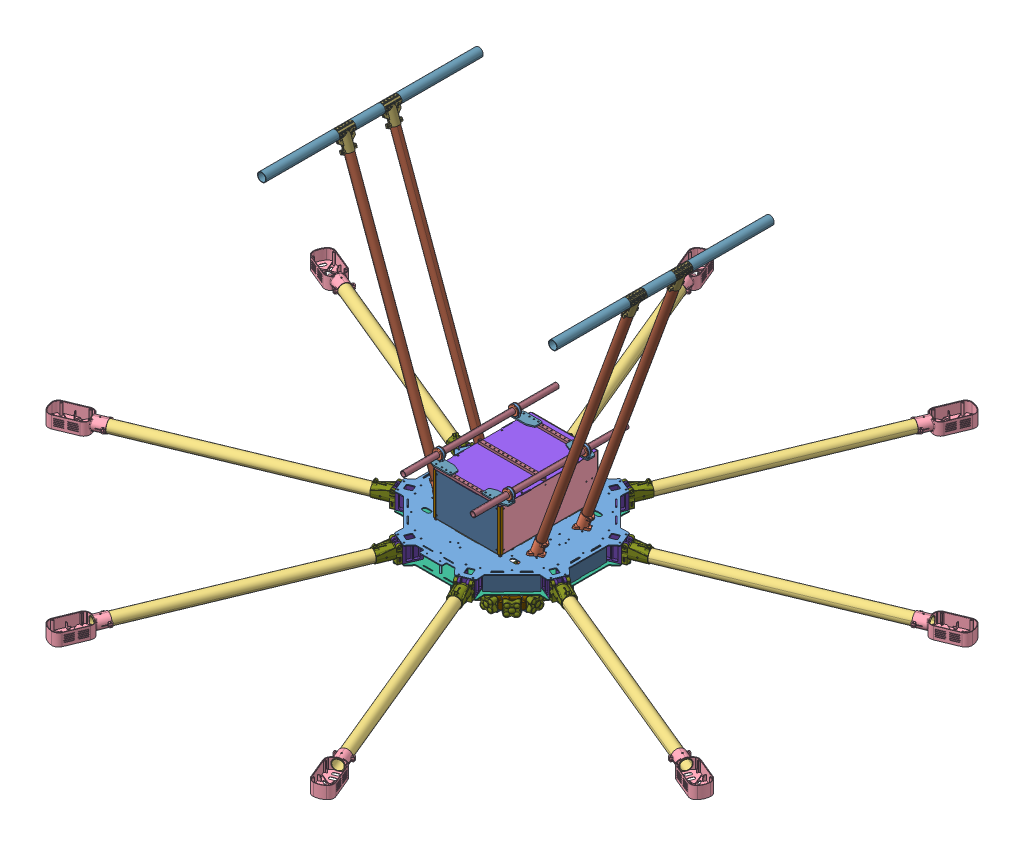
SolidWorks assembly X8_Max-frame with Teraranger mount, configuration Default. Lengths in mm.
Overall size (1514.24 796.89 1514.24).
169 component instances, 38 part files, 6 mates.
Components (placement in the parent):
- X8 Max Assem-2.STEP-1: X8 Max Assem-2.STEP [Default] at origin size (1514.24 672.95 1514.24)
  - Ensamblaje Caja de baterias.STEP-1: Ensamblaje Caja de baterias.STEP [Default] at (-4.4674 -57.1682 2.6) size (189.05 134.33 225.1)
    - Soporte Tubos Assem.STEP-1: Soporte Tubos Assem.STEP [Default] at (29.4599 122.1453 316.55) x (-1 0 0) z (0 0 1) size (30.05 30.05 9.5)
      - Soporte Tubos 1.2.STEP-1: Soporte Tubos 1.2.STEP [Default] at (-57.7355 6.8516 -2.2) size (22 22 4.4)
      - Soporte Tubos 1.1.STEP-1: Soporte Tubos 1.1.STEP [Default] at (-57.7355 6.8516 -4.7) x (0.866047 0.499962 0) z (0 0 1) size (22 22 9.5)
    - Soporte Tubos Assem.STEP-2: Soporte Tubos Assem.STEP [Default] at (-129.5401 122.1453 316.55) x (-1 0 0) z (0 0 1) size (30.05 30.05 9.5)
      - Soporte Tubos 1.2.STEP-1: Soporte Tubos 1.2.STEP [Default] at (-57.7355 6.8516 -2.2) size (22 22 4.4)
      - Soporte Tubos 1.1.STEP-1: Soporte Tubos 1.1.STEP [Default] at (-57.7355 6.8516 -4.7) x (0.866047 0.499962 0) z (0 0 1) size (22 22 9.5)
    - Soporte Tubos Assem.STEP-3: Soporte Tubos Assem.STEP [Default] at (29.4599 122.1453 143.55) x (-1 0 0) z (0 0 1) size (30.05 30.05 9.5)
      - Soporte Tubos 1.2.STEP-1: Soporte Tubos 1.2.STEP [Default] at (-57.7355 6.8516 -2.2) size (22 22 4.4)
      - Soporte Tubos 1.1.STEP-1: Soporte Tubos 1.1.STEP [Default] at (-57.7355 6.8516 -4.7) x (0.866047 0.499962 0) z (0 0 1) size (22 22 9.5)
    - Soporte Tubos Assem.STEP-4: Soporte Tubos Assem.STEP [Default] at (-129.5401 122.1453 143.55) x (-1 0 0) z (0 0 1) size (30.05 30.05 9.5)
      - Soporte Tubos 1.2.STEP-1: Soporte Tubos 1.2.STEP [Default] at (-57.7355 6.8516 -2.2) size (22 22 4.4)
      - Soporte Tubos 1.1.STEP-1: Soporte Tubos 1.1.STEP [Default] at (-57.7355 6.8516 -4.7) x (0.866047 0.499962 0) z (0 0 1) size (22 22 9.5)
    - Frame Standard FC Bateria Placa Superior.STEP-1: Frame Standard FC Bateria Placa Superior.STEP [Default] at (7.6954 -1.0063 222.5) size (155 1 223)
    - Frame Standard FC Bateria Pared Lateral Cerradura.STEP-1: Frame Standard FC Bateria Pared Lateral Cerradura.STEP [Default] at (84.1954 47.4937 219.45) x (0 0 -1) z (0 1 0) size (216 1 97)
    - Frame Standard FC Bateria Pared Lateral Visagras.STEP-1: Frame Standard FC Bateria Pared Lateral Visagras.STEP [Default] at (-67.8046 47.4937 219.45) x (0 0 -1) z (0 1 0) size (216 1 97)
    - Columna Soporte lateral.STEP-1: Columna Soporte lateral.STEP [Default] at (-65.3046 94.9937 130.05) x (1 0 0) z (0 -1 0) size (5 7 95)
    - Columna Soporte lateral.STEP-2: Columna Soporte lateral.STEP [Default] at (-65.3046 94.9937 230.05) x (1 0 0) z (0 -1 0) size (5 7 95)
    - Columna Soporte lateral.STEP-3: Columna Soporte lateral.STEP [Default] at (80.6954 94.9937 130.05) x (-1 0 0) z (0 -1 0) size (5 7 95)
    - Columna Soporte lateral.STEP-4: Columna Soporte lateral.STEP [Default] at (80.6954 94.9937 230.05) x (-1 0 0) z (0 -1 0) size (5 7 95)
    - Separador 95mm.STEP-1: Separador 95mm.STEP [Default] at (80.6954 94.9937 180.05) x (0.181479 0 -0.983395) z (0 -1 0) size (4.5 4.5 95)
    - Separador 95mm.STEP-2: Separador 95mm.STEP [Default] at (80.6954 94.9937 280.05) x (-0.225094 0 -0.974337) z (0 -1 0) size (4.5 4.5 95)
    - Separador 95mm.STEP-3: Separador 95mm.STEP [Default] at (-65.3046 -0.0063 180.05) x (-0.848491 0 0.529211) z (0 1 0) size (4.5 4.5 95)
    - Separador 95mm.STEP-4: Separador 95mm.STEP [Default] at (-65.3046 94.9937 280.05) x (0.989316 0 -0.145784) z (0 -1 0) size (4.5 4.5 95)
    - Frame Standard FC Bateria Placa Inferior.STEP-1: Frame Standard FC Bateria Placa Inferior.STEP [Default] at (7.6954 94.9937 222.5) size (155 1 223)
    - Columna Soporte Esquinas.STEP-1: Columna Soporte Esquinas.STEP [Default] at (-68.8046 94.9937 333.5) x (1 0 0) z (0 -1 0) size (10.5 10.5 95)
    - Columna Soporte Esquinas.STEP-2: Columna Soporte Esquinas.STEP [Default] at (84.1954 -0.0063 333.5) x (-1 0 0) z (0 1 0) size (10.5 10.5 95)
    - Frame Standard FC Bateria Placa Delantera.STEP-1: Frame Standard FC Bateria Placa Delantera.STEP [Default] at (7.6954 47.4437 333.5) x (1 0 0) z (0 1 0) size (140.5 1 97)
    - Frame Standard FC Bateria Separador.STEP-1: Frame Standard FC Bateria Separador.STEP [Default] at (-65.3046 -1.0063 230.05) x (0 0 1) z (1 0 0) size (206.1 3 8.1)
    - Frame Standard FC Bateria Separador.STEP-2: Frame Standard FC Bateria Separador.STEP [Default] at (80.6954 -4.0063 230.05) x (0 0 1) z (-1 0 0) size (206.1 3 8.1)
    - Frame Standard FC Bateria Placa Trasera.STEP-1: Frame Standard FC Bateria Placa Trasera.STEP [Default] at (9.1954 48.2937 111.45) x (1 0 0) z (0 1 0) size (151 1.5 95.4)
    - Rieles.STEP-1: Rieles.STEP [Default] at (7.6954 95.9937 330.05) x (1 0 0) z (0 1 0) size (153 7.6 5.5)
    - Rieles.STEP-2: Rieles.STEP [Default] at (7.6954 95.9937 130.05) x (1 0 0) z (0 1 0) size (153 7.6 5.5)
    - Rieles.STEP-3: Rieles.STEP [Default] at (7.6954 95.9937 230.05) x (1 0 0) z (0 1 0) size (153 7.6 5.5)
    - Frame Standard FC Bateria Placa Soporte Tubos.STEP-1: Frame Standard FC Bateria Placa Soporte Tubos.STEP [Default] at (7.1954 104.2937 340.05) x (-1 0 0) z (0 0 1) size (55.5 2.8 23.5)
    - Frame Standard FC Bateria Placa Soporte Tubos.STEP-2: Frame Standard FC Bateria Placa Soporte Tubos.STEP [Default] at (8.1954 101.4937 340.05) size (55.5 2.8 23.5)
    - Frame Standard FC Bateria Placa Soporte Tubos.STEP-3: Frame Standard FC Bateria Placa Soporte Tubos.STEP [Default] at (8.1954 104.2937 120.05) x (1 0 0) z (0 0 -1) size (55.5 2.8 23.5)
    - Frame Standard FC Bateria Placa Soporte Tubos.STEP-4: Frame Standard FC Bateria Placa Soporte Tubos.STEP [Default] at (7.1954 101.4937 120.05) x (-1 0 0) z (0 0 -1) size (55.5 2.8 23.5)
  - F25A201903000_ASM.STEP-1: F25A201903000_ASM.STEP [Default] at (50.0183 -63.1744 77.2248) x (0.92388 0 0.382683) z (0 1 0) size (32.71 81.51 45.27)
    - ADMI4DDBV6KN_ASM.STEP-1: ADMI4DDBV6KN_ASM.STEP [Default] at origin size (32.71 81.51 45.27)
      - ADMI4DDBV6KN_1.STEP-1: ADMI4DDBV6KN_1.STEP [Default] at origin size (9 9 21)
      - ADMI4DDBV6KN_2.STEP-1: ADMI4DDBV6KN_2.STEP [Default] at origin size (32.51 45.52 39.01)
      - ADMI4DDBV6KN_3.STEP-1: ADMI4DDBV6KN_3.STEP [Default] at origin size (32.51 45.51 38.51)
      - ADMI4DDBV6KN_4.STEP-1: ADMI4DDBV6KN_4.STEP [Default] at origin size (32.5 3 3)
  - F25A201903000_ASM.STEP-2: F25A201903000_ASM.STEP [Default] at (146.2159 -63.1744 155.8336) x (0.382683 0 0.92388) z (0 1 0) size (32.71 81.51 45.27)
    - ADMI4DDBV6KN_ASM.STEP-1: ADMI4DDBV6KN_ASM.STEP [Default] at origin size (32.71 81.51 45.27)
      - ADMI4DDBV6KN_1.STEP-1: ADMI4DDBV6KN_1.STEP [Default] at origin size (9 9 21)
      - ADMI4DDBV6KN_2.STEP-1: ADMI4DDBV6KN_2.STEP [Default] at origin size (32.51 45.52 39.01)
      - ADMI4DDBV6KN_3.STEP-1: ADMI4DDBV6KN_3.STEP [Default] at origin size (32.51 45.51 38.51)
      - ADMI4DDBV6KN_4.STEP-1: ADMI4DDBV6KN_4.STEP [Default] at origin size (32.5 3 3)
  - F25A201903000_ASM.STEP-3: F25A201903000_ASM.STEP [Default] at (158.6531 -63.1744 279.4403) x (-0.382683 0 0.92388) z (0 1 0) size (32.71 81.51 45.27)
    - ADMI4DDBV6KN_ASM.STEP-1: ADMI4DDBV6KN_ASM.STEP [Default] at origin size (32.71 81.51 45.27)
      - ADMI4DDBV6KN_1.STEP-1: ADMI4DDBV6KN_1.STEP [Default] at origin size (9 9 21)
      - ADMI4DDBV6KN_2.STEP-1: ADMI4DDBV6KN_2.STEP [Default] at origin size (32.51 45.52 39.01)
      - ADMI4DDBV6KN_3.STEP-1: ADMI4DDBV6KN_3.STEP [Default] at origin size (32.51 45.51 38.51)
      - ADMI4DDBV6KN_4.STEP-1: ADMI4DDBV6KN_4.STEP [Default] at origin size (32.5 3 3)
  - F25A201903000_ASM.STEP-4: F25A201903000_ASM.STEP [Default] at (80.0444 -63.1744 375.6379) x (-0.92388 0 0.382683) z (0 1 0) size (32.71 81.51 45.27)
    - ADMI4DDBV6KN_ASM.STEP-1: ADMI4DDBV6KN_ASM.STEP [Default] at origin size (32.71 81.51 45.27)
      - ADMI4DDBV6KN_1.STEP-1: ADMI4DDBV6KN_1.STEP [Default] at origin size (9 9 21)
      - ADMI4DDBV6KN_2.STEP-1: ADMI4DDBV6KN_2.STEP [Default] at origin size (32.51 45.52 39.01)
      - ADMI4DDBV6KN_3.STEP-1: ADMI4DDBV6KN_3.STEP [Default] at origin size (32.51 45.51 38.51)
      - ADMI4DDBV6KN_4.STEP-1: ADMI4DDBV6KN_4.STEP [Default] at origin size (32.5 3 3)
  - F25A201903000_ASM.STEP-5: F25A201903000_ASM.STEP [Default] at (-43.5623 -63.1744 388.0752) x (-0.92388 0 -0.382683) z (0 1 0) size (32.71 81.51 45.27)
    - ADMI4DDBV6KN_ASM.STEP-1: ADMI4DDBV6KN_ASM.STEP [Default] at origin size (32.71 81.51 45.27)
      - ADMI4DDBV6KN_1.STEP-1: ADMI4DDBV6KN_1.STEP [Default] at origin size (9 9 21)
      - ADMI4DDBV6KN_2.STEP-1: ADMI4DDBV6KN_2.STEP [Default] at origin size (32.51 45.52 39.01)
      - ADMI4DDBV6KN_3.STEP-1: ADMI4DDBV6KN_3.STEP [Default] at origin size (32.51 45.51 38.51)
      - ADMI4DDBV6KN_4.STEP-1: ADMI4DDBV6KN_4.STEP [Default] at origin size (32.5 3 3)
  - F25A201903000_ASM.STEP-6: F25A201903000_ASM.STEP [Default] at (-139.7599 -63.1744 309.4664) x (-0.382683 0 -0.92388) z (0 1 0) size (32.71 81.51 45.27)
    - ADMI4DDBV6KN_ASM.STEP-1: ADMI4DDBV6KN_ASM.STEP [Default] at origin size (32.71 81.51 45.27)
      - ADMI4DDBV6KN_1.STEP-1: ADMI4DDBV6KN_1.STEP [Default] at origin size (9 9 21)
      - ADMI4DDBV6KN_2.STEP-1: ADMI4DDBV6KN_2.STEP [Default] at origin size (32.51 45.52 39.01)
      - ADMI4DDBV6KN_3.STEP-1: ADMI4DDBV6KN_3.STEP [Default] at origin size (32.51 45.51 38.51)
      - ADMI4DDBV6KN_4.STEP-1: ADMI4DDBV6KN_4.STEP [Default] at origin size (32.5 3 3)
  - F25A201903000_ASM.STEP-7: F25A201903000_ASM.STEP [Default] at (-152.1972 -63.1744 185.8597) x (0.382683 0 -0.92388) z (0 1 0) size (32.71 81.51 45.27)
    - ADMI4DDBV6KN_ASM.STEP-1: ADMI4DDBV6KN_ASM.STEP [Default] at origin size (32.71 81.51 45.27)
      - ADMI4DDBV6KN_1.STEP-1: ADMI4DDBV6KN_1.STEP [Default] at origin size (9 9 21)
      - ADMI4DDBV6KN_2.STEP-1: ADMI4DDBV6KN_2.STEP [Default] at origin size (32.51 45.52 39.01)
      - ADMI4DDBV6KN_3.STEP-1: ADMI4DDBV6KN_3.STEP [Default] at origin size (32.51 45.51 38.51)
      - ADMI4DDBV6KN_4.STEP-1: ADMI4DDBV6KN_4.STEP [Default] at origin size (32.5 3 3)
  - F25A201903000_ASM.STEP-8: F25A201903000_ASM.STEP [Default] at (-73.5884 -63.1744 89.6621) x (0.92388 0 -0.382683) z (0 1 0) size (32.71 81.51 45.27)
    - ADMI4DDBV6KN_ASM.STEP-1: ADMI4DDBV6KN_ASM.STEP [Default] at origin size (32.71 81.51 45.27)
      - ADMI4DDBV6KN_1.STEP-1: ADMI4DDBV6KN_1.STEP [Default] at origin size (9 9 21)
      - ADMI4DDBV6KN_2.STEP-1: ADMI4DDBV6KN_2.STEP [Default] at origin size (32.51 45.52 39.01)
      - ADMI4DDBV6KN_3.STEP-1: ADMI4DDBV6KN_3.STEP [Default] at origin size (32.51 45.51 38.51)
      - ADMI4DDBV6KN_4.STEP-1: ADMI4DDBV6KN_4.STEP [Default] at origin size (32.5 3 3)
  - Frame X8 Max FC Cuerpo Plato Inferior.STEP-1: Frame X8 Max FC Cuerpo Plato Inferior.STEP [Default] at (3.228 -61.1744 232.65) x (1 0 0) z (0 -1 0) size (378.3 378.3 2)
  - Soporte Pata.STEP-1: Soporte Pata.STEP [Default] at (-102.0735 -69.0149 180.4) x (0.939693 0.34202 0) z (-0.34202 0.939693 0) size (28.4 36.17 38.5)
  - Soporte Pata.STEP-2: Soporte Pata.STEP [Default] at (-102.0735 -69.0149 284.9) x (0.939693 0.34202 0) z (-0.34202 0.939693 0) size (28.4 36.17 38.5)
  - Soporte Pata.STEP-3: Soporte Pata.STEP [Default] at (108.5295 -69.0149 284.9) x (-0.939693 0.34202 0) z (0.34202 0.939693 0) size (28.4 36.17 38.5)
  - Soporte Pata.STEP-4: Soporte Pata.STEP [Default] at (108.5295 -69.0149 180.4) x (-0.939693 0.34202 0) z (0.34202 0.939693 0) size (28.4 36.17 38.5)
  - Frame X8 Max FC Tubo Brazo.STEP-1: Frame X8 Max FC Tubo Brazo.STEP [Default] at (83.4002 -81.6744 39.0972) x (0.202315 -0.975728 0.083802) z (0.901455 0.218985 0.373395) size (25 524 25)
  - MINI-DJZ-25-SLIM.STEP-1: MINI-DJZ-25-SLIM.STEP [Default] at (300.4461 -98.1744 -484.8979) x (-0.382683 0 0.92388) z (0 1 0) size (106.78 43.6 30.2)
  - MINI-DJZ-25-SLIM.STEP-2: MINI-DJZ-25-SLIM.STEP [Default] at (720.7759 -98.1744 -64.5681) x (-0.92388 0 0.382683) z (0 1 0) size (106.78 43.6 30.2)
  - MINI-DJZ-25-SLIM.STEP-3: MINI-DJZ-25-SLIM.STEP [Default] at (720.7759 -98.1744 529.8681) x (-0.92388 0 -0.382683) z (0 1 0) size (106.78 43.6 30.2)
  - MINI-DJZ-25-SLIM.STEP-4: MINI-DJZ-25-SLIM.STEP [Default] at (300.4461 -98.1744 950.1979) x (-0.382683 0 -0.92388) z (0 1 0) size (106.78 43.6 30.2)
  - MINI-DJZ-25-SLIM.STEP-5: MINI-DJZ-25-SLIM.STEP [Default] at (-293.9901 -98.1744 950.1979) x (0.382683 0 -0.92388) z (0 1 0) size (106.78 43.6 30.2)
  - MINI-DJZ-25-SLIM.STEP-6: MINI-DJZ-25-SLIM.STEP [Default] at (-714.3199 -98.1744 529.8681) x (0.92388 0 -0.382683) z (0 1 0) size (106.78 43.6 30.2)
  - MINI-DJZ-25-SLIM.STEP-7: MINI-DJZ-25-SLIM.STEP [Default] at (-714.3199 -98.1744 -64.5681) x (0.92388 0 0.382683) z (0 1 0) size (106.78 43.6 30.2)
  - MINI-DJZ-25-SLIM.STEP-8: MINI-DJZ-25-SLIM.STEP [Default] at (-293.9901 -98.1744 -484.8979) x (0.382683 0 0.92388) z (0 1 0) size (106.78 43.6 30.2)
  - Frame X8 Max FC Tubo Brazo.STEP-2: Frame X8 Max FC Tubo Brazo.STEP [Default] at (196.7808 -81.6744 152.4778) x (0.083802 -0.975728 0.202315) z (0.373395 0.218985 0.901455) size (25 524 25)
  - Frame X8 Max FC Tubo Brazo.STEP-3: Frame X8 Max FC Tubo Brazo.STEP [Default] at (196.7808 -81.6744 312.8222) x (-0.083802 -0.975728 0.202315) z (-0.373395 0.218985 0.901455) size (25 524 25)
  - Frame X8 Max FC Tubo Brazo.STEP-4: Frame X8 Max FC Tubo Brazo.STEP [Default] at (83.4002 -81.6744 426.2028) x (-0.202315 -0.975728 0.083802) z (-0.901455 0.218985 0.373395) size (25 524 25)
  - Frame X8 Max FC Tubo Brazo.STEP-5: Frame X8 Max FC Tubo Brazo.STEP [Default] at (-76.9442 -81.6744 426.2028) x (-0.202315 -0.975728 -0.083802) z (-0.901455 0.218985 -0.373395) size (25 524 25)
  - Frame X8 Max FC Tubo Brazo.STEP-6: Frame X8 Max FC Tubo Brazo.STEP [Default] at (-190.3248 -81.6744 312.8222) x (-0.083802 -0.975728 -0.202315) z (-0.373395 0.218985 -0.901455) size (25 524 25)
  - Frame X8 Max FC Tubo Brazo.STEP-7: Frame X8 Max FC Tubo Brazo.STEP [Default] at (-190.3248 -81.6744 152.4778) x (0.083802 -0.975728 -0.202315) z (0.373395 0.218985 -0.901455) size (25 524 25)
  - Frame X8 Max FC Tubo Brazo.STEP-8: Frame X8 Max FC Tubo Brazo.STEP [Default] at (-76.9442 -81.6744 39.0972) x (0.202315 -0.975728 -0.083802) z (0.901455 0.218985 -0.373395) size (25 524 25)
  - Separador 37mm.STEP-1: Separador 37mm.STEP [Default] at (3.228 -63.1744 70.15) x (0.954625 0 0.297809) z (0 -1 0) size (4.5 4.5 37)
  - Separador 37mm.STEP-2: Separador 37mm.STEP [Default] at (118.1328 -63.1744 117.7451) x (0.464439 0 0.885605) z (0 -1 0) size (4.5 4.5 37)
  - Separador 37mm.STEP-3: Separador 37mm.STEP [Default] at (165.728 -63.1744 232.65) x (-0.297809 0 0.954625) z (0 -1 0) size (4.5 4.5 37)
  - Separador 37mm.STEP-4: Separador 37mm.STEP [Default] at (118.1328 -63.1744 347.5549) x (-0.885605 0 0.464439) z (0 -1 0) size (4.5 4.5 37)
  - Separador 37mm.STEP-5: Separador 37mm.STEP [Default] at (3.228 -63.1744 395.15) x (-0.954625 0 -0.297809) z (0 -1 0) size (4.5 4.5 37)
  - Separador 37mm.STEP-6: Separador 37mm.STEP [Default] at (-111.6769 -63.1744 347.5549) x (-0.464439 0 -0.885605) z (0 -1 0) size (4.5 4.5 37)
  - Separador 37mm.STEP-7: Separador 37mm.STEP [Default] at (-159.272 -63.1744 232.65) x (0.297809 0 -0.954625) z (0 -1 0) size (4.5 4.5 37)
  - Separador 37mm.STEP-8: Separador 37mm.STEP [Default] at (-111.6769 -63.1744 117.7451) x (0.885605 0 -0.464439) z (0 -1 0) size (4.5 4.5 37)
  - Separador 37mm.STEP-9: Separador 37mm.STEP [Default] at (-25.4733 -63.1744 163.359) x (1 0 0) z (0 -1 0) size (4.5 4.5 37)
  - Separador 37mm.STEP-10: Separador 37mm.STEP [Default] at (31.9293 -63.1744 163.359) x (0.707107 0 0.707107) z (0 -1 0) size (4.5 4.5 37)
  - Separador 37mm.STEP-11: Separador 37mm.STEP [Default] at (72.519 -63.1744 203.9487) x (0 0 1) z (0 -1 0) size (4.5 4.5 37)
  - Separador 37mm.STEP-12: Separador 37mm.STEP [Default] at (72.519 -63.1744 261.3513) x (-0.707107 0 0.707107) z (0 -1 0) size (4.5 4.5 37)
  - Separador 37mm.STEP-13: Separador 37mm.STEP [Default] at (31.9293 -63.1744 301.941) x (-1 0 0) z (0 -1 0) size (4.5 4.5 37)
  - Separador 37mm.STEP-14: Separador 37mm.STEP [Default] at (-25.4733 -63.1744 301.941) x (-0.707107 0 -0.707107) z (0 -1 0) size (4.5 4.5 37)
  - Separador 37mm.STEP-15: Separador 37mm.STEP [Default] at (-66.063 -63.1744 261.3513) x (0 0 -1) z (0 -1 0) size (4.5 4.5 37)
  - Separador 37mm.STEP-16: Separador 37mm.STEP [Default] at (-66.063 -63.1744 203.9487) x (0.707107 0 -0.707107) z (0 -1 0) size (4.5 4.5 37)
  - Frame X8 Max FC Cuerpo Plato Superior.STEP-1: Frame X8 Max FC Cuerpo Plato Superior.STEP [Default] at (3.228 -100.1744 232.65) x (1 0 0) z (0 -1 0) size (378.3 378.3 2)
  - Frame X8 Max FC Cuerpo Placa Controladora.STEP-1: Frame X8 Max FC Cuerpo Placa Controladora.STEP [Default] at (3.228 -102.1744 232.65) x (1 0 0) z (0 -1 0) size (151.9 151.9 2)
  - Frame X8 Max FC Cuerpo Pared Lateral Oled.STEP-1: Frame X8 Max FC Cuerpo Pared Lateral Oled.STEP [Default] at (122.9058 -80.6744 113.255) x (0.707107 0 0.707107) z (-0.707107 0 0.707107) size (94 43 2)
  - Frame X8 Max FC Cuerpo Pared Lateral XT90.STEP-1: Frame X8 Max FC Cuerpo Pared Lateral XT90.STEP [Default] at (3.428 -80.6744 63.6) size (94 43 2)
  - Frame X8 Max FC Cuerpo Pared Lateral.STEP-1: Frame X8 Max FC Cuerpo Pared Lateral.STEP [Default] at (-116.167 -80.6744 112.9722) x (0.707107 0 -0.707107) z (0.707107 0 0.707107) size (94 43 2)
  - Frame X8 Max FC Cuerpo Pared Lateral.STEP-2: Frame X8 Max FC Cuerpo Pared Lateral.STEP [Default] at (-163.822 -80.6744 232.45) x (0 0 1) z (-1 0 0) size (94 43 2)
  - Frame X8 Max FC Cuerpo Pared Lateral.STEP-3: Frame X8 Max FC Cuerpo Pared Lateral.STEP [Default] at (121.2088 -80.6744 350.9136) x (0.707107 0 -0.707107) z (0.707107 0 0.707107) size (94 43 2)
  - Frame X8 Max FC Cuerpo Pared Lateral.STEP-4: Frame X8 Max FC Cuerpo Pared Lateral.STEP [Default] at (-115.0356 -80.6744 350.6308) x (0.707107 0 0.707107) z (-0.707107 0 0.707107) size (94 43 2)
  - Frame X8 Max FC Cuerpo Pared Lateral.STEP-5: Frame X8 Max FC Cuerpo Pared Lateral.STEP [Default] at (170.278 -80.6744 232.85) x (0 0 -1) z (1 0 0) size (94 43 2)
  - Frame X8 Max FC Tubo Pata Superior.STEP-1: Frame X8 Max FC Tubo Pata Superior.STEP [Default] at (112.6337 -57.7385 284.9) x (0.883022 -0.321394 -0.34202) z (0.34202 0.939693 0) size (18 18 645)
  - Frame X8 Max FC Tubo Pata Superior.STEP-2: Frame X8 Max FC Tubo Pata Superior.STEP [Default] at (-106.1778 -57.7385 284.9) x (0.161002 0.0586 -0.985213) z (-0.34202 0.939693 0) size (18 18 645)
  - Frame X8 Max FC Tubo Pata Superior.STEP-3: Frame X8 Max FC Tubo Pata Superior.STEP [Default] at (-106.1778 -57.7385 180.4) x (0.883022 0.321394 0.34202) z (-0.34202 0.939693 0) size (18 18 645)
  - Frame X8 Max FC Tubo Pata Superior.STEP-4: Frame X8 Max FC Tubo Pata Superior.STEP [Default] at (112.6337 -57.7385 180.4) x (0.883022 -0.321394 -0.34202) z (0.34202 0.939693 0) size (18 18 645)
  - Patas.STEP-1: Patas.STEP [Default] at (-315.8361 518.293 180.4) x (0 0 1) z (-0.34202 0.939693 0) size (38 20 47.5)
  - Patas.STEP-2: Patas.STEP [Default] at (322.2921 518.293 284.9) x (0 0 -1) z (0.34202 0.939693 0) size (38 20 47.5)
  - Patas.STEP-3: Patas.STEP [Default] at (-315.8361 518.293 284.9) x (0 0 1) z (-0.34202 0.939693 0) size (38 20 47.5)
  - Patas.STEP-4: Patas.STEP [Default] at (322.2921 518.293 180.4) x (0 0 -1) z (0.34202 0.939693 0) size (38 20 47.5)
  - Frame X8 Max FC Tubo Payload.STEP-1: Frame X8 Max FC Tubo Payload.STEP [Default] at (-76.272 58.1256 51.45) x (1 0 0) z (0 -1 0) size (12 350 12)
  - Frame X8 Max FC Tubo Payload.STEP-2: Frame X8 Max FC Tubo Payload.STEP [Default] at (82.728 58.1256 51.45) x (1 0 0) z (0 -1 0) size (12 350 12)
  - Frame X8 Max FC Tubo Pata Inferior.STEP-1: Frame X8 Max FC Tubo Pata Inferior.STEP [Default] at (335.1178 553.5315 -23.6) size (20 20 495)
  - Frame X8 Max FC Tubo Pata Inferior.STEP-2: Frame X8 Max FC Tubo Pata Inferior.STEP [Default] at (-328.6619 553.5315 -23.6) size (20 20 495)
- X8 Max mount lidar-1: X8 Max mount lidar [Default] at (3.228 -102.1744 232.65) x (-1 0 0) z (0 0 1) size (270 65 270)
- Teraranger tower evo with mount-1: Teraranger tower evo with mount [Default] at (3.228 -218.9744 232.65) x (1 0 0) z (0 -1 0) size (122.6 122.1 63.36)
  - Teraranger Tower EVO.step-1: Teraranger Tower EVO.step [Default] at origin size (122.6 122.1 42.36)
    - TeraRangerEvo.step-1: TeraRangerEvo.step [Default] at (0.7 -42.5 -3.3) size (30.36 17.79 29.9)
      - TeraRangerEvo_EVO_60m_centro.step-1: TeraRangerEvo_EVO_60m_centro.step [Default] at (3.8782 -2.2298 -38.14) x (-1 0 0) z (0 0 -1) size (30.36 17.79 29.9)
    - Lower.step-1: Lower.step [Default] at (0 0 -9.8) size (98.02 98.02 36.8)
      - upper PCB.step-1: upper PCB.step [Default] at (0 0 -2) size (41 51 2)
      - Lower Frame.step-1: Lower Frame.step [Default] at origin size (98.02 98.02 36.8)
    - TeraRangerEvo_1.step-1: TeraRangerEvo_1.step [Default] at (30.547 -29.5571 -3.3) x (0.707107 0.707107 0) z (0 0 1) size (30.36 17.79 29.9)
      - TeraRangerEvo_EVO_60m_centro.step-1: TeraRangerEvo_EVO_60m_centro.step [Default] at (3.8782 -2.7298 -38.14) x (-1 0 0) z (0 0 -1) size (30.36 17.79 29.9)
    - TeraRangerEvo_2.step-1: TeraRangerEvo_2.step [Default] at (42.5 0.7 -3.3) x (0 1 0) z (0 0 1) size (30.36 17.79 29.9)
      - TeraRangerEvo_EVO_60m_centro.step-1: TeraRangerEvo_EVO_60m_centro.step [Default] at (3.8782 -2.7298 -38.14) x (-1 0 0) z (0 0 -1) size (30.36 17.79 29.9)
    - TeraRangerEvo_3.step-1: TeraRangerEvo_3.step [Default] at (29.5571 30.547 -3.3) x (-0.707107 0.707107 0) z (0 0 1) size (30.36 17.79 29.9)
      - TeraRangerEvo_EVO_60m_centro.step-1: TeraRangerEvo_EVO_60m_centro.step [Default] at (3.8782 -2.7298 -38.14) x (-1 0 0) z (0 0 -1) size (30.36 17.79 29.9)
    - TeraRangerEvo_4.step-1: TeraRangerEvo_4.step [Default] at (-0.7 42.5 -3.3) x (-1 0 0) z (0 0 1) size (30.36 17.79 29.9)
      - TeraRangerEvo_EVO_60m_centro.step-1: TeraRangerEvo_EVO_60m_centro.step [Default] at (3.8782 -2.7298 -38.14) x (-1 0 0) z (0 0 -1) size (30.36 17.79 29.9)
    - TeraRangerEvo_5.step-1: TeraRangerEvo_5.step [Default] at (-30.547 29.5571 -3.3) x (-0.707107 -0.707107 0) z (0 0 1) size (30.36 17.79 29.9)
      - TeraRangerEvo_EVO_60m_centro.step-1: TeraRangerEvo_EVO_60m_centro.step [Default] at (3.8782 -2.7298 -38.14) x (-1 0 0) z (0 0 -1) size (30.36 17.79 29.9)
    - TeraRangerEvo_6.step-1: TeraRangerEvo_6.step [Default] at (-42.5 -0.7 -3.3) x (0 -1 0) z (0 0 1) size (30.36 17.79 29.9)
      - TeraRangerEvo_EVO_60m_centro.step-1: TeraRangerEvo_EVO_60m_centro.step [Default] at (3.8782 -2.7298 -38.14) x (-1 0 0) z (0 0 -1) size (30.36 17.79 29.9)
    - TeraRangerEvo_7.step-1: TeraRangerEvo_7.step [Default] at (-29.5571 -30.547 -3.3) x (0.707107 -0.707107 0) z (0 0 1) size (30.36 17.79 29.9)
      - TeraRangerEvo_EVO_60m_centro.step-1: TeraRangerEvo_EVO_60m_centro.step [Default] at (3.8782 -2.7298 -38.14) x (-1 0 0) z (0 0 -1) size (30.36 17.79 29.9)
    - Upper.step-1: Upper.step [Default] at origin size (98.02 98.02 11.56)
  - Teraranger mount lidar new-1: Teraranger mount lidar new [Default] at (0 0 -30.8) x (0 -1 0) z (1 0 0) size (110 21 110)
Mates (geometry in assembly coordinates):
- Concentric1: concentric: cylinder of X8 Max Assem-2.STEP-1/Frame X8 Max FC Cuerpo Plato Superior.STEP-1 through (3.228 -100.1744 355.15) axis (0 -1 0) radius 1.55; cylinder of X8 Max mount lidar-1 through (3.228 -105.3744 355.15) axis (0 1 0) radius 1.6
- Concentric2: concentric: cylinder of X8 Max Assem-2.STEP-1/Frame X8 Max FC Cuerpo Plato Superior.STEP-1 through (3.228 -100.1744 110.15) axis (0 -1 0) radius 1.55; cylinder of X8 Max mount lidar-1 through (3.228 -105.3744 110.15) axis (0 1 0) radius 1.6
- Coincident1: coincident anti-aligned: plane of X8 Max Assem-2.STEP-1/Frame X8 Max FC Cuerpo Plato Superior.STEP-1 through (3.228 -102.1744 232.65) normal (0 -1 0); plane of X8 Max mount lidar-1 through (3.228 -102.1744 232.65) normal (0 1 0)
- Concentric3: concentric: cylinder of X8 Max mount lidar-1 through (3.228 -167.1744 182.65) axis (0 1 0) radius 1.6; cylinder of Teraranger tower evo with mount-1/Teraranger mount lidar new-1 through (3.228 -214.9709 182.65) axis (0 1 0) radius 1.6
- Concentric4: concentric: cylinder of X8 Max mount lidar-1 through (3.228 -167.1744 282.65) axis (0 1 0) radius 1.6; cylinder of Teraranger tower evo with mount-1/Teraranger mount lidar new-1 through (3.228 -188.1744 282.65) axis (0 1 0) radius 1.6
- Coincident2: coincident anti-aligned: plane of X8 Max mount lidar-1 through (3.228 -167.1744 232.65) normal (0 -1 0); plane of Teraranger tower evo with mount-1/Teraranger mount lidar new-1 through (3.228 -167.1744 232.65) normal (0 1 0)
